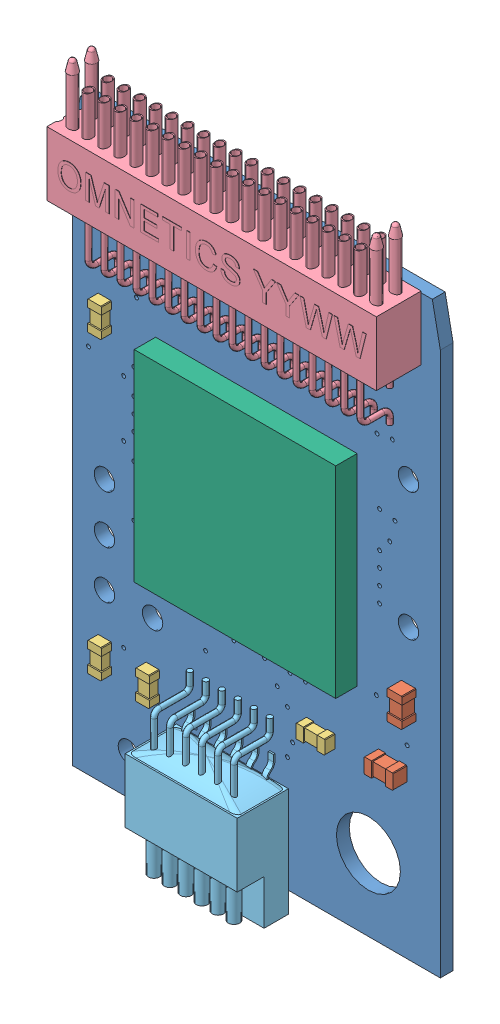
SolidWorks assembly RHD2132_16_headstage, configuration Default. Lengths in mm.
Overall size (14.61 26.43 2.55).
10 component instances, 6 part files, 20 mates.
Components (placement in the parent):
- RHD2216_RHD2132_headstage_PCB-1: RHD2216_RHD2132_headstage_PCB [Default] at origin size (14.61 23.18 0.51)
- 0402c_2320560-1: 0402c_2320560 [Default] at (13.335 8.89 0.508) x (0 -1 0) z (0 0 1) size (1.15 0.6 0.55)
- 0402c_2320560-2: 0402c_2320560 [Default] at (12.7 6.35 0.508) size (1.15 0.6 0.55)
- 0402r_1430758-1: 0402r_1430758 [Default] at (1.27 16.18 0.508) x (0 -1 0) z (0 0 1) size (1.15 0.55 0.4)
- 0402r_1430758-2: 0402r_1430758 [Default] at (3.175 4.445 0.508) x (0 1 0) z (0 0 1) size (1.15 0.55 0.4)
- 0402r_1430758-3: 0402r_1430758 [Default] at (1.27 4.445 0.508) x (0 1 0) z (0 0 1) size (1.15 0.55 0.4)
- 0402r_1430758-4: 0402r_1430758 [Default] at (9.8425 6.0325 0.508) size (1.15 0.55 0.4)
- A79025-001-1: A79025-001 [Default] at (6.0325 21.971 2.286) size (13.15 7.44 2.12)
- A79623-001-1: A79623-001 [Default] at (6.35 3.4925 0.508) x (1 0 0) z (0 -1 0) size (4.45 2.05 6.53)
- QFN_8x8mm-1: QFN_8x8mm [Default] at (3.3025 8.3825 0.508) x (1 0 0) z (0 -1 0) size (8 0.85 8)
Mates (geometry in assembly coordinates):
- Coincident1: coincident anti-aligned: plane of RHD2216_RHD2132_headstage-1 through (0 0 0.508) normal (0 0 1); plane of A79025-001-1 through (13.843 20.701 0.508) normal (0 0 -1)
- Parallel1: parallel aligned: plane of RHD2216_RHD2132_headstage-1 through (0.3175 23.1775 0.508) normal (0 1 0); plane of A79025-001-1 through (13.843 23.241 2.286) normal (0 1 0)
- Distance1: distance = 0.0635 mm: line of A79025-001-1 through (0.762 23.241 0.508) axis (1 0 0); line of RHD2216_RHD2132_headstage-1 through (14.2875 23.1775 0.508) axis (-1 0 0)
- Distance3: distance = 0.762 mm: line of A79025-001-1 through (0.762 20.7271 0.508) axis (0 1 0); line of RHD2216_RHD2132_headstage-1 through (0 21.59 0.508) axis (0 -1 0)
- Coincident5: coincident anti-aligned: plane of RHD2216_RHD2132_headstage-1 through (0 0 0.508) normal (0 0 1); plane of QFN_8x8mm-1 through (3.3025 8.3825 0.508) normal (0 0 -1)
- Parallel2: parallel aligned: plane of RHD2216_RHD2132_headstage-1 through (14.605 21.59 0.508) normal (1 0 0); plane of QFN_8x8mm-1 through (11.3025 8.3825 1.358) normal (1 0 0)
- Coincident6: coincident anti-aligned: plane of RHD2216_RHD2132_headstage-1 through (0 0 0.508) normal (0 0 1); plane of A79623-001-1 through (6.35 3.4925 0.508) normal (0 0 -1)
- Parallel3: parallel aligned: plane of RHD2216_RHD2132_headstage-1 through (14.605 0 0.508) normal (0 -1 0); plane of A79623-001-1 through (8.5725 -0.8255 0.508) normal (0 -1 0)
- Coincident7: coincident anti-aligned: plane of RHD2216_RHD2132_headstage-1 through (0 0 0.508) normal (0 0 1); plane of 0402r_1430758-1 through (2.095 16.18 0.508) normal (0 0 -1)
- Parallel4: parallel aligned: plane of RHD2216_RHD2132_headstage-1 through (14.605 0 0.508) normal (0 -1 0); plane of 0402r_1430758-1 through (1.02 15.605 0.908) normal (0 -1 0)
- Coincident8: coincident anti-aligned: plane of RHD2216_RHD2132_headstage-1 through (0 0 0.508) normal (0 0 1); plane of 0402r_1430758-3 through (0.445 4.445 0.508) normal (0 0 -1)
- Parallel5: parallel aligned: plane of RHD2216_RHD2132_headstage-1 through (14.605 0 0.508) normal (0 -1 0); plane of 0402r_1430758-3 through (1.02 3.87 0.908) normal (0 -1 0)
- Coincident9: coincident anti-aligned: plane of RHD2216_RHD2132_headstage-1 through (0 0 0.508) normal (0 0 1); plane of 0402r_1430758-2 through (2.35 4.445 0.508) normal (0 0 -1)
- Parallel6: parallel aligned: plane of RHD2216_RHD2132_headstage-1 through (14.605 0 0.508) normal (0 -1 0); plane of 0402r_1430758-2 through (2.925 3.87 0.908) normal (0 -1 0)
- Coincident10: coincident anti-aligned: plane of RHD2216_RHD2132_headstage-1 through (0 0 0.508) normal (0 0 1); plane of 0402r_1430758-4 through (9.8425 6.8575 0.508) normal (0 0 -1)
- Parallel7: parallel aligned: plane of RHD2216_RHD2132_headstage-1 through (14.605 21.59 0.508) normal (1 0 0); plane of 0402r_1430758-4 through (10.4175 5.7825 0.908) normal (1 0 0)
- Coincident11: coincident anti-aligned: plane of RHD2216_RHD2132_headstage-1 through (0 0 0.508) normal (0 0 1); plane of 0402c_2320560-2 through (12.7 7.2 0.508) normal (0 0 -1)
- Parallel8: parallel aligned: plane of RHD2216_RHD2132_headstage-1 through (14.605 21.59 0.508) normal (1 0 0); plane of 0402c_2320560-2 through (13.275 6.075 1.058) normal (1 0 0)
- Coincident12: coincident anti-aligned: plane of RHD2216_RHD2132_headstage-1 through (0 0 0.508) normal (0 0 1); plane of 0402c_2320560-1 through (14.185 8.89 0.508) normal (0 0 -1)
- Parallel9: parallel aligned: plane of RHD2216_RHD2132_headstage-1 through (14.605 0 0.508) normal (0 -1 0); plane of 0402c_2320560-1 through (13.06 8.315 1.058) normal (0 -1 0)
